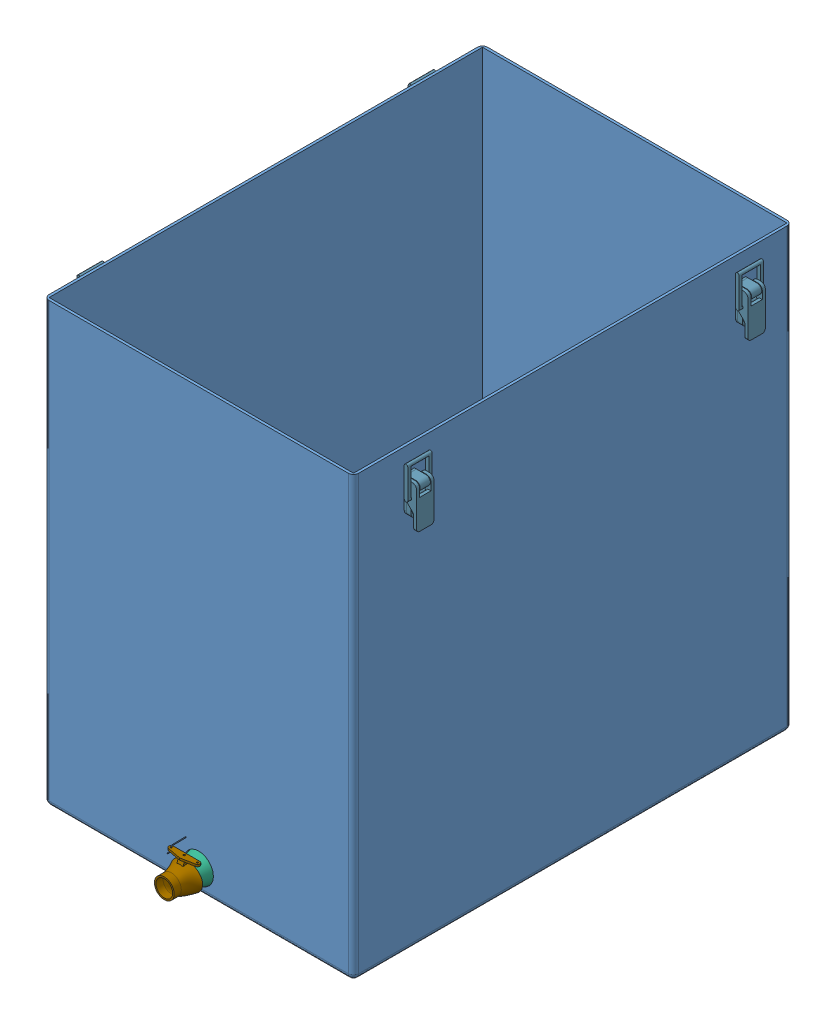
SolidWorks assembly impeller_styrofoam sub assy, configuration Default. Lengths in mm.
Overall size (336.3 431.8 465.68).
22 component instances, 15 part files, 18 mates.
Components (placement in the parent):
- styrofoam impeller mount-1: styrofoam impeller mount [Default] at (-143.924 -118.1594 -226.3788) size (304.8 431.8 431.8)
- assembly 25mm impeller jet drive-1: assembly 25mm impeller jet drive [Default] at (8.466 -96.2939 191.7462) x (0 0 1) z (-1 0 0) size (175.66 47.97 37.3)
  - jet drive for 25mm impeller-1: jet drive for 25mm impeller [Default] at (-2.105 -21.3255 0) size (90 39.15 37)
  - shaft-1: shaft [Default] at (-69.955 -0.679 0) x (1 0 0) z (0 -0.374675 0.927156) size (85 3 3)
  - RS365 DC Motor-1: RS365 DC Motor [Default] at (-77.105 -0.679 0) x (1 0 0) z (0 1 0) size (51 27.5 27.5)
  - shaft coupler-1: shaft coupler [Default] at (-63.411 -0.679 0) x (-1 0 0) z (0 -0.042922 -0.999078) size (20 9 9)
  - stator-1: stator [Default] at (-4.955 -0.679 0) size (35.93 37.32 37.3)
  - impeller 25min OD-1: impeller 25min OD [Default] at (11.045 -0.679 0) x (0 0.907746 0.419521) z (0 -0.419521 0.907746) size (24.22 20 24.19)
  - servo towerpro sg90-1: servo towerpro sg90 [Default] at (-55.63 10.746 -16.6125) x (1 0 0) z (0 -1 0) size (32.05 31 21.88)
  - nozzle-1: nozzle [Default] at (25.545 -0.679 0) x (0 0 -1) z (0 -1 0) size (31.46 22.02 31.51)
  - wire-1: wire [Default] at origin size (95.63 10.1 6.02)
  - bearing-1: bearing [Default] at (-48.4939 -0.679 0) x (0 -0.407486 -0.913211) z (-1 0 0) size (4 4 4)
  - bearing-2: bearing [Default] at (-58.105 -0.679 0) x (0 0.170235 0.985404) z (-1 0 0) size (4 4 4)
  - bearing-3: bearing [Default] at (15.045 -0.679 0) x (0 0.944365 0.328901) z (-1 0 0) size (4 4 4)
  - hull-1: hull [Default] at origin size (333.75 30.44 61.92) (hidden)
  - pan head cross recess screw_iso-1: pan head cross recess screw_iso [ISO 7045 - M2.5 x 5 - Z - 5N] at (-87.155 -0.679 8) x (-1 0 0) z (0 -0.924225 -0.381849) size (7.05 5 5)
  - pan head cross recess screw_iso-2: pan head cross recess screw_iso [ISO 7045 - M2.5 x 5 - Z - 5N] at (-87.155 -0.679 -8) x (-1 0 0) z (0 -0.85199 -0.523557) size (7.05 5 5)
  - countersunk flat head cross recess screw_iso-2: countersunk flat head cross recess screw_iso [ISO 7046-1 - M2.5 x 5 - Z - 5N] at (-92.105 -13.679 0) size (5 4.7 4.7)
- latch_thrusterbin-1: latch_thrusterbin [Default] at (176.626 356.9025 -150.495) x (0 -1 0) z (1 0 0) size (57 24 15.75)
- latch_thrusterbin-2: latch_thrusterbin [Default] at (176.626 356.9025 175.7459) x (0 -1 0) z (1 0 0) size (57 24 15.75)
- latch_thrusterbin-4: latch_thrusterbin [Default] at (-159.674 356.9025 125.1971) x (0 -1 0) z (-1 0 0) size (57 24 15.75)
- latch_thrusterbin-5: latch_thrusterbin [Default] at (-159.674 356.9025 -201.0438) x (0 -1 0) z (-1 0 0) size (57 24 15.75)
Mates (geometry in assembly coordinates):
- Parallel1: parallel anti-aligned: line of styrofoam impeller mount-1 through (-141.384 313.6406 202.8812) axis (1 0 0); line of assembly 25mm impeller jet drive-1/jet drive for 25mm impeller-1 through (26.966 -115.6194 189.6412) axis (-1 0 0)
- Coincident3: coincident anti-aligned: plane of styrofoam impeller mount-1 through (-143.924 -115.6194 205.4212) normal (0 1 0); plane of assembly 25mm impeller jet drive-1/jet drive for 25mm impeller-1 through (8.466 -115.6194 144.6412) normal (0 -1 0)
- Coincident4: coincident anti-aligned: plane of styrofoam impeller mount-1 through (-8.034 -118.1594 187.6412) normal (1 0 0); plane of assembly 25mm impeller jet drive-1/jet drive for 25mm impeller-1 through (-8.034 -115.6194 187.6412) normal (-1 0 0)
- Coincident6: coincident: line of styrofoam impeller mount-1 through (24.986 -118.1594 187.6412) axis (0 1 0); plane of assembly 25mm impeller jet drive-1/jet drive for 25mm impeller-1 through (24.966 -115.6194 187.6412) normal (0 0 1)
- Parallel2: parallel anti-aligned: line of styrofoam impeller mount-1 through (-141.384 313.6406 202.8812) axis (1 0 0); line of assembly 25mm impeller jet drive-2/jet drive for 25mm impeller-1 through (289.856 -110.5394 189.6412) axis (-1 0 0)
- Coincident7: coincident anti-aligned: plane of styrofoam impeller mount-1 through (-143.924 -110.5394 205.4212) normal (0 1 0); plane of assembly 25mm impeller jet drive-2/jet drive for 25mm impeller-1 through (271.356 -110.5394 144.6412) normal (0 -1 0)
- Coincident8: coincident anti-aligned: plane of styrofoam impeller mount-1 through (254.856 -118.1594 187.6412) normal (1 0 0); plane of assembly 25mm impeller jet drive-2/jet drive for 25mm impeller-1 through (254.856 -110.5394 187.6412) normal (-1 0 0)
- Coincident9: coincident anti-aligned: plane of styrofoam impeller mount-1 through (287.876 -118.1594 187.6412) normal (0 0 -1); plane of assembly 25mm impeller jet drive-2/jet drive for 25mm impeller-1 through (287.856 -110.5394 187.6412) normal (0 0 1)
- Coincident10: coincident anti-aligned: plane of styrofoam impeller mount-1 through (160.876 -118.1594 205.4212) normal (1 0 0); plane of latch_thrusterbin-1 through (160.876 263.5906 -175.7694) normal (-1 0 0)
- Distance1: distance = 22.86 mm aligned: plane of styrofoam impeller mount-1 through (-143.924 313.6406 205.4212) normal (0 1 0); plane of latch_thrusterbin-1 through (160.876 290.7806 -170.7694) normal (0 1 0)
- Coincident12: coincident anti-aligned: plane of styrofoam impeller mount-1 through (160.876 -118.1594 205.4212) normal (1 0 0); plane of latch_thrusterbin-2 through (160.876 269.9406 150.4715) normal (-1 0 0)
- Distance2: distance = 22.86 mm aligned: plane of styrofoam impeller mount-1 through (-143.924 313.6406 205.4212) normal (0 1 0); plane of latch_thrusterbin-2 through (160.876 290.7806 155.4715) normal (0 1 0)
- Coincident14: coincident anti-aligned: plane of styrofoam impeller mount-1 through (-143.924 -118.1594 205.4212) normal (-1 0 0); plane of latch_thrusterbin-4 through (-143.924 259.7806 150.4715) normal (1 0 0)
- Distance4: distance = 22.86 mm aligned: plane of styrofoam impeller mount-1 through (-143.924 313.6406 205.4212) normal (0 1 0); plane of latch_thrusterbin-4 through (-143.924 290.7806 145.4715) normal (0 1 0)
- Distance5: distance = 22.86 mm aligned: plane of styrofoam impeller mount-1 through (-143.924 313.6406 205.4212) normal (0 1 0); plane of latch_thrusterbin-5 through (-143.924 290.7806 -180.7694) normal (0 1 0)
- Coincident15: coincident anti-aligned: plane of styrofoam impeller mount-1 through (-143.924 -118.1594 205.4212) normal (-1 0 0); plane of latch_thrusterbin-5 through (-143.924 259.7806 -175.7694) normal (1 0 0)
- Coincident16: coincident aligned: plane of latch_thrusterbin-2 through (160.876 300.9406 155.4715) normal (0 0 1); plane of latch_thrusterbin-4 through (-143.924 290.7806 155.4715) normal (0 0 1)
- Coincident17: coincident aligned: plane of latch_thrusterbin-1 through (160.876 294.5906 -170.7694) normal (0 0 1); plane of latch_thrusterbin-5 through (-143.924 290.7806 -170.7694) normal (0 0 1)
